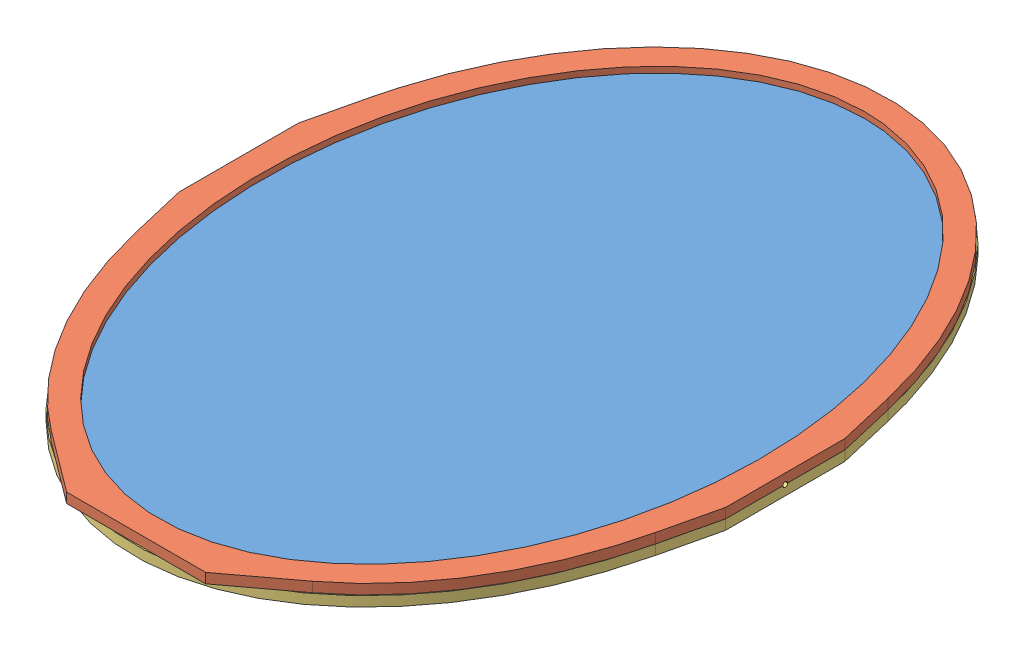
SolidWorks assembly Mirror Assembly, configuration Default. Lengths in mm.
Overall size (550 20 760).
3 component instances, 3 part files, 6 mates.
Components (placement in the parent):
- Mirror-1: Mirror [Default] at (-116.0082 27.9493 42.2276) size (520 4 730)
- Mirror Front-1: Mirror Front [Default] at (-116.0082 27.9493 42.2276) size (550 10 756.61)
- Mirror Back-1: Mirror Back [Default] at (-116.0082 27.9493 42.2276) x (-1 0 0) z (0 0 1) size (550 10 760)
Mates (geometry in assembly coordinates):
- Coincident1: coincident: point of Mirror-1; point of Mirror Front-1
- Coincident2: coincident: point of Mirror-1; point of Mirror Front-1
- Coincident3: coincident: point of Mirror-1; point of Mirror Front-1
- Coincident4: coincident: point of Mirror Front-1; point of Mirror Back-1
- Coincident6: coincident: point of Mirror Front-1; point of Mirror Back-1
- Coincident7: coincident anti-aligned: plane of Mirror Front-1 through (-116.0082 27.9493 42.2276) normal (0 -1 0); plane of Mirror Back-1 through (-116.0082 27.9493 42.2276) normal (0 1 0)
